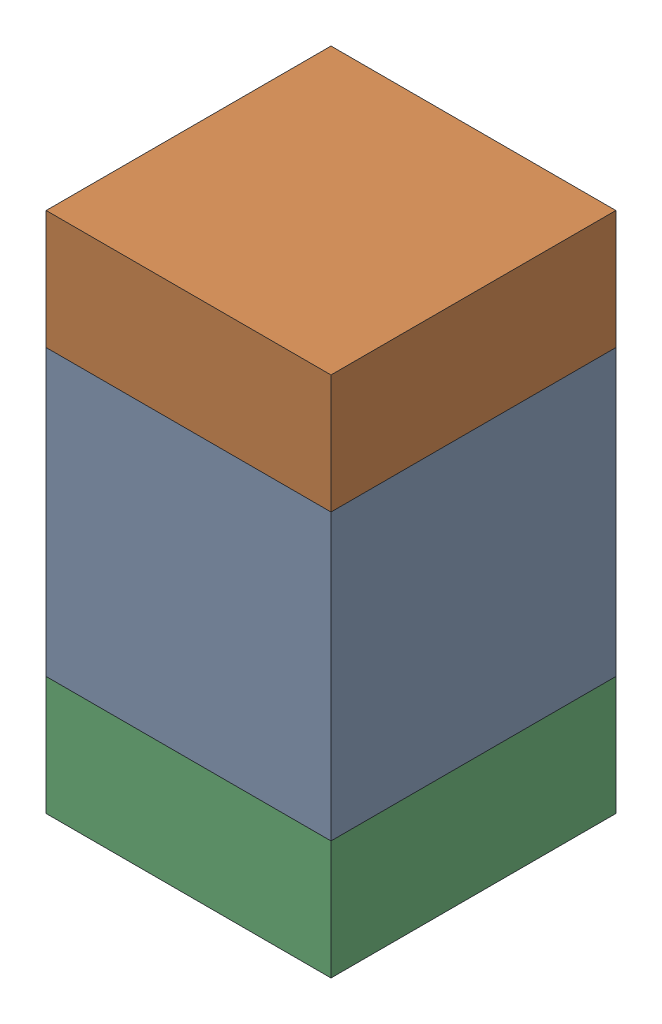
SolidWorks assembly C403PCB, configuration Default. Lengths in mm.
Overall size (0.6 1.1 0.6).
6 component instances, 2 part files, 0 mates.
Components (placement in the parent):
- 761606048-1: 761606048 [Default] at (77.8 81.5 0) size (0.6 0.6 0.6)
  - Extruded_9-1: Extruded_9 [Default] at origin size (0.6 0.6 0.6)
- 854785296-1: 854785296 [Default] at (77.8 81.925 0) size (0.6 0.25 0.6)
  - Extruded_10-1: Extruded_10 [Default] at origin size (0.6 0.25 0.6)
- 854785296-2: 854785296 [Default] at (77.8 81.075 0) size (0.6 0.25 0.6)
  - Extruded_10-1: Extruded_10 [Default] at origin size (0.6 0.25 0.6)
